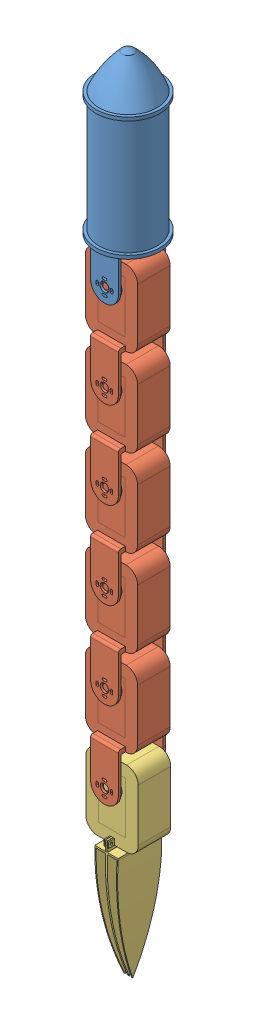
SolidWorks assembly bus_assembly_total_5, configuration 預設. Lengths in mm.
Overall size (443.2 602.57 55).
7 component instances, 3 part files, 24 mates.
Components (placement in the parent):
- base_link-2: base_link [預設] at (-200.3488 -8.0568 -97.9891) size (55 179.98 55)
- link1-1: link1 [預設] at (-286.3308 -349.3248 -5.4136) x (0 1 0) z (0 0 -1) size (45 107 40.5)
- link1-2: link1 [預設] at (-286.3308 -125.2248 -5.4136) x (0 1 0) z (0 0 -1) size (45 107 40.5)
- link1-3: link1 [預設] at (-286.3308 -199.9248 -5.4136) x (0 1 0) z (0 0 -1) size (45 107 40.5)
- link1-4: link1 [預設] at (-286.3308 -424.0248 -5.4136) x (0 1 0) z (0 0 -1) size (45 107 40.5)
- link1-5: link1 [預設] at (-286.3308 -274.6248 -5.4136) x (0 1 0) z (0 0 -1) size (45 107 40.5)
- link6-1: link6 [預設] at (-162.426 -442.9917 52.8279) x (0 1 0) z (0 0 -1) size (170.09 49.79 38.13)
Mates (geometry in assembly coordinates):
- 重合/共線/共點1: coincident: plane of base_link-2 through (-179.3308 -93.8197 20.2609) normal (0 0 -1); plane of link1-2 through (-179.3308 -93.8197 20.2609) normal (0 0 1)
- 重合/共線/共點2: coincident: plane of base_link-2 through (-179.3308 -93.8197 -16.2391) normal (0 0 1); plane of link1-2 through (-179.3308 -93.8197 -16.2391) normal (0 0 -1)
- 同軸心1: concentric: cylinder of base_link-2 through (-179.3308 -93.8197 20.2609) axis (0 0 1) radius 4; cylinder of link1-2 through (-179.3308 -93.8197 16.2609) axis (0 0 1) radius 4
- 重合/共線/共點3: coincident: plane of base_link-2 through (-180.3808 -86.6197 20.2609) normal (0 -1 0); plane of link1-2 through (-178.2808 -86.6197 16.2609) normal (0 -1 0)
- 重合/共線/共點4: coincident: plane of link1-2 through (-179.3308 -168.5197 20.2609) normal (0 0 -1); plane of link1-3 through (-179.3308 -168.5197 20.2609) normal (0 0 1)
- 重合/共線/共點5: coincident: plane of link1-2 through (-179.3308 -168.5197 -16.2391) normal (0 0 1); plane of link1-3 through (-179.3308 -168.5197 -16.2391) normal (0 0 -1)
- 同軸心2: concentric: cylinder of link1-2 through (-179.3308 -168.5197 -16.2391) axis (0 0 -1) radius 4; cylinder of link1-3 through (-179.3308 -168.5197 -17.2391) axis (0 0 1) radius 4
- 平行1: parallel: plane of link1-2 through (-172.2308 -169.5697 -16.2391) normal (-1 0 0); plane of link1-3 through (-172.1308 -169.5697 -17.2391) normal (-1 0 0)
- 重合/共線/共點7: coincident: plane of link1-3 through (-179.3308 -243.2197 -16.2391) normal (0 0 1); plane of link1-5 through (-179.3308 -243.2197 -16.2391) normal (0 0 -1)
- 重合/共線/共點8: coincident: plane of link1-3 through (-179.3308 -243.2197 20.2609) normal (0 0 -1); plane of link1-5 through (-179.3308 -243.2197 20.2609) normal (0 0 1)
- 同軸心3: concentric: cylinder of link1-3 through (-179.3308 -243.2197 22.2609) axis (0 0 -1) radius 3.7; cylinder of link1-5 through (-179.3308 -243.2197 16.2609) axis (0 0 1) radius 4
- 平行2: parallel: plane of link1-3 through (-178.2808 -236.1197 22.2609) normal (0 -1 0); plane of link1-5 through (-178.2808 -236.0197 16.2609) normal (0 -1 0)
- 重合/共線/共點10: coincident: plane of link1-1 through (-179.3308 -317.9197 20.2609) normal (0 0 1); plane of link1-5 through (-179.3308 -317.9197 20.2609) normal (0 0 -1)
- 重合/共線/共點11: coincident: plane of link1-1 through (-179.3308 -317.9197 -16.2391) normal (0 0 -1); plane of link1-5 through (-179.3308 -317.9197 -16.2391) normal (0 0 1)
- 同軸心4: concentric: cylinder of link1-1 through (-179.3308 -317.9197 16.2609) axis (0 0 1) radius 4; cylinder of link1-5 through (-179.3308 -317.9197 22.2609) axis (0 0 -1) radius 3.7
- 平行3: parallel: plane of link1-1 through (-178.2808 -310.7197 16.2609) normal (0 -1 0); plane of link1-5 through (-178.2808 -310.8197 22.2609) normal (0 -1 0)
- 重合/共線/共點13: coincident: plane of link1-1 through (-179.3308 -392.6197 20.2609) normal (0 0 -1); plane of link1-4 through (-179.3308 -392.6197 20.2609) normal (0 0 1)
- 重合/共線/共點14: coincident: plane of link1-1 through (-179.3308 -392.6197 -16.2391) normal (0 0 1); plane of link1-4 through (-179.3308 -392.6197 -16.2391) normal (0 0 -1)
- 同軸心5: concentric: cylinder of link1-1 through (-179.3308 -392.6197 -16.2391) axis (0 0 -1) radius 4; cylinder of link1-4 through (-179.3308 -392.6197 -17.2391) axis (0 0 1) radius 4
- 重合/共線/共點15: coincident: plane of link1-1 through (-178.2808 -397.8197 -16.2391) normal (0 -1 0); plane of link1-4 through (-178.2808 -397.8197 -17.2391) normal (0 -1 0)
- 重合/共線/共點16: coincident: plane of link1-4 through (-179.3308 -467.3197 20.2609) normal (0 0 -1); plane of link6-1 through (-179.3308 -467.3197 20.2609) normal (0 0 1)
- 平行4: parallel: plane of link1-4 through (-179.3308 -467.3197 -16.2391) normal (0 0 1); plane of link6-1 through (-179.3308 -467.3197 -16.7391) normal (0 0 -1)
- 同軸心7: concentric: cylinder of link1-4 through (-179.3308 -467.3197 22.2609) axis (0 0 -1) radius 3.7; cylinder of link6-1 through (-179.3308 -467.3197 16.2609) axis (0 0 1) radius 4
- 平行5: parallel: plane of link1-4 through (-178.2808 -460.2197 22.2609) normal (0 -1 0); plane of link6-1 through (-178.2808 -460.1197 16.2609) normal (0 -1 0)
